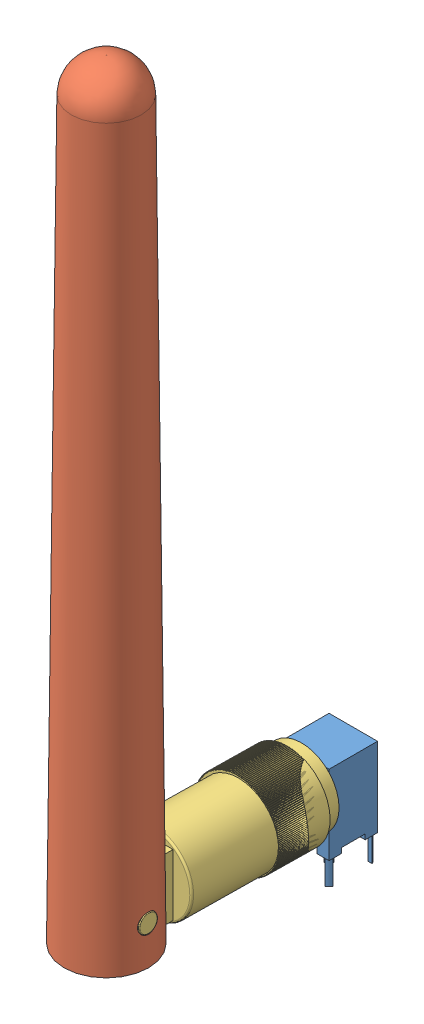
SolidWorks assembly angtenfinal, configuration Default. Lengths in mm.
Overall size (11.11 105.24 37.61).
6 component instances, 5 part files, 0 mates.
Components (placement in the parent):
- Truangten.step-1: Truangten.step [Default] at (-0.6208 0.2927 12.5083) x (0 0 1) z (0 1 0) size (14.2 7.33 13.53)
- antenna_WiFi_RP-SMA_conn.step-1: antenna_WiFi_RP-SMA_conn.step [Default] at (-0.6199 2.3044 41.4648) x (1 0 0) z (0 1 0) size (11.11 30.9 100.5)
  - ant.step-1: ant.step [Default] at (0 -0.0027 0.0017) size (11 10.91 100)
  - conn_body.step-1: conn_body.step [Default] at (-0.0138 -0.0027 0.0017) size (11.11 29.25 11.01)
  - SMA_threads.step-1: SMA_threads.step [Default] at (-0.0138 -0.0027 0.0017) size (8 3 8)
  - socket.step-1: socket.step [Default] at (-0.0138 -0.2827 0.0017) size (1.27 5.64 1.27)
